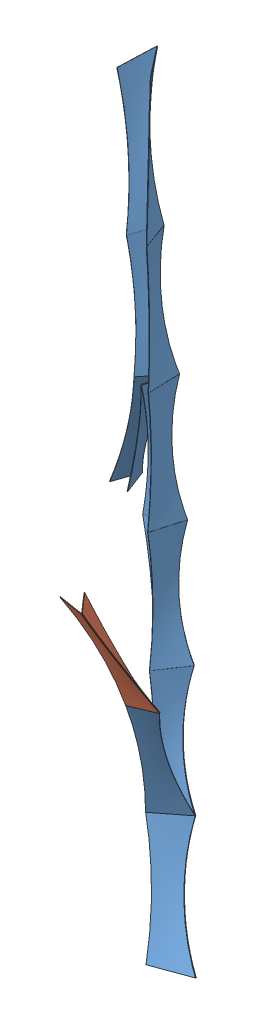
SolidWorks assembly oneLeg, configuration Default. Lengths in mm.
Overall size (836.99 2438.54 897.01).
9 component instances, 2 part files, 24 mates.
Components (placement in the parent):
- legSegment-1: legSegment [1] at origin size (290.9 407.18 209.57)
- legSegment-2: legSegment [2] at (0 406.4 0) x (0.951057 0 -0.309017) z (0.309017 0 0.951057) size (199.52 407.01 141.57)
- legSegment-3: legSegment [3] at (0 812.8 0) x (0.809017 0 -0.587785) z (0.587785 0 0.809017) size (166.84 406.98 178.95)
- legSegment-4: legSegment [4] at (0 1219.2 0) x (0.587785 0 -0.809017) z (0.809017 0 0.587785) size (120.6 406.9 178.61)
- legSegment-5: legSegment [5] at (0 1625.6 0) x (0.309017 0 -0.951057) z (0.951057 0 0.309017) size (147.7 407.08 200.06)
- legSegment-6: legSegment [6] at (0 2032 0) x (0 0 -1) z (1 0 0) size (302.37 407.28 267.53)
- legSegment-7: legSegment [2.1] at (0 406.4 0) x (0.951057 0 -0.309017) z (0.309017 0 0.951057) size (155.13 406.86 125.74)
- legSegment-8: legSegment [4.1] at (0 1219.2 0) x (-0.017452 0 -0.999848) z (0.999848 0 -0.017452) size (114.05 407.03 177.06)
- asshole-1: asshole [Default] at (0 812.8 0) x (0.99863 0 -0.052336) z (0.052336 0 0.99863) size (200.22 407.56 253.31)
Mates (geometry in assembly coordinates):
- Coincident1: coincident aligned: line of legSegment-1 through (0 0 0) axis (0 1 0); line of legSegment-2 through (0 406.4 0) axis (0 1 0)
- Coincident2: coincident aligned: plane of legSegment-1 through (0 406.4 0) normal (0 1 0); plane of legSegment-2
- Coincident4: coincident aligned: line of legSegment-1 through (0 406.4 0) axis (0.951057 0 -0.309017); line of legSegment-2 through (0 406.4 0) axis (0.951057 0 -0.309017)
- Coincident5: coincident aligned: line of legSegment-1 through (0 0 0) axis (0 1 0); line of legSegment-3 through (0 812.8 0) axis (0 1 0)
- Coincident6: coincident aligned: plane of legSegment-2; plane of legSegment-3
- Coincident7: coincident aligned: line of legSegment-2 through (0 812.8 0) axis (0.809017 0 -0.587785); line of legSegment-3 through (0 812.8 0) axis (0.809017 0 -0.587785)
- Coincident8: coincident aligned: line of legSegment-1 through (0 0 0) axis (0 1 0); line of legSegment-4 through (0 1219.2 0) axis (0 1 0)
- Coincident9: coincident aligned: plane of legSegment-3; plane of legSegment-4
- Coincident11: coincident aligned: line of legSegment-3 through (0 1219.2 0) axis (0.587785 0 -0.809017); line of legSegment-4 through (0 1219.2 0) axis (0.587785 0 -0.809017)
- Coincident12: coincident aligned: line of legSegment-1 through (0 0 0) axis (0 1 0); line of legSegment-5 through (0 1625.6 0) axis (0 1 0)
- Coincident13: coincident aligned: plane of legSegment-4; plane of legSegment-5
- Coincident14: coincident aligned: line of legSegment-4 through (0 1625.6 0) axis (0.309017 0 -0.951057); line of legSegment-5 through (0 1625.6 0) axis (0.309017 0 -0.951057)
- Coincident15: coincident aligned: line of legSegment-1 through (0 0 0) axis (0 1 0); line of legSegment-6 through (0 2032 0) axis (0 1 0)
- Coincident16: coincident aligned: plane of legSegment-5; plane of legSegment-6
- Coincident17: coincident aligned: line of legSegment-5 through (0 2032 0) axis (0 0 -1); line of legSegment-6 through (0 2032 0) axis (0 0 -1)
- Coincident18: coincident aligned: line of legSegment-1 through (0 0 0) axis (0 1 0); line of legSegment-7 through (0 406.4 0) axis (0 1 0)
- Coincident19: coincident aligned: plane of legSegment-2; plane of legSegment-7
- Coincident20: coincident aligned: line of legSegment-2 through (0 406.4 0) axis (0.951057 0 -0.309017); line of legSegment-7 through (0 406.4 0) axis (0.951057 0 -0.309017)
- Coincident21: coincident aligned: line of legSegment-1 through (0 0 0) axis (0 1 0); line of legSegment-8 through (0 1219.2 0) axis (0 1 0)
- Coincident22: coincident aligned: plane of legSegment-4; plane of legSegment-8
- Parallel2: parallel aligned: line of legSegment-5 through (0 1625.6 0) axis (0.309017 0 -0.951057); line of legSegment-8 through (0 1219.2 0) axis (0.309017 0 -0.951057)
- Coincident23: coincident aligned: line of legSegment-1 through (0 0 0) axis (0 1 0); line of asshole-1 through (0 812.8 0) axis (0 1 0)
- Coincident24: coincident aligned: plane of legSegment-3; plane of asshole-1
- Coincident25: coincident: point of legSegment-7; line of asshole-1 through (0 812.8 0) axis (0.99863 0 -0.052336)
